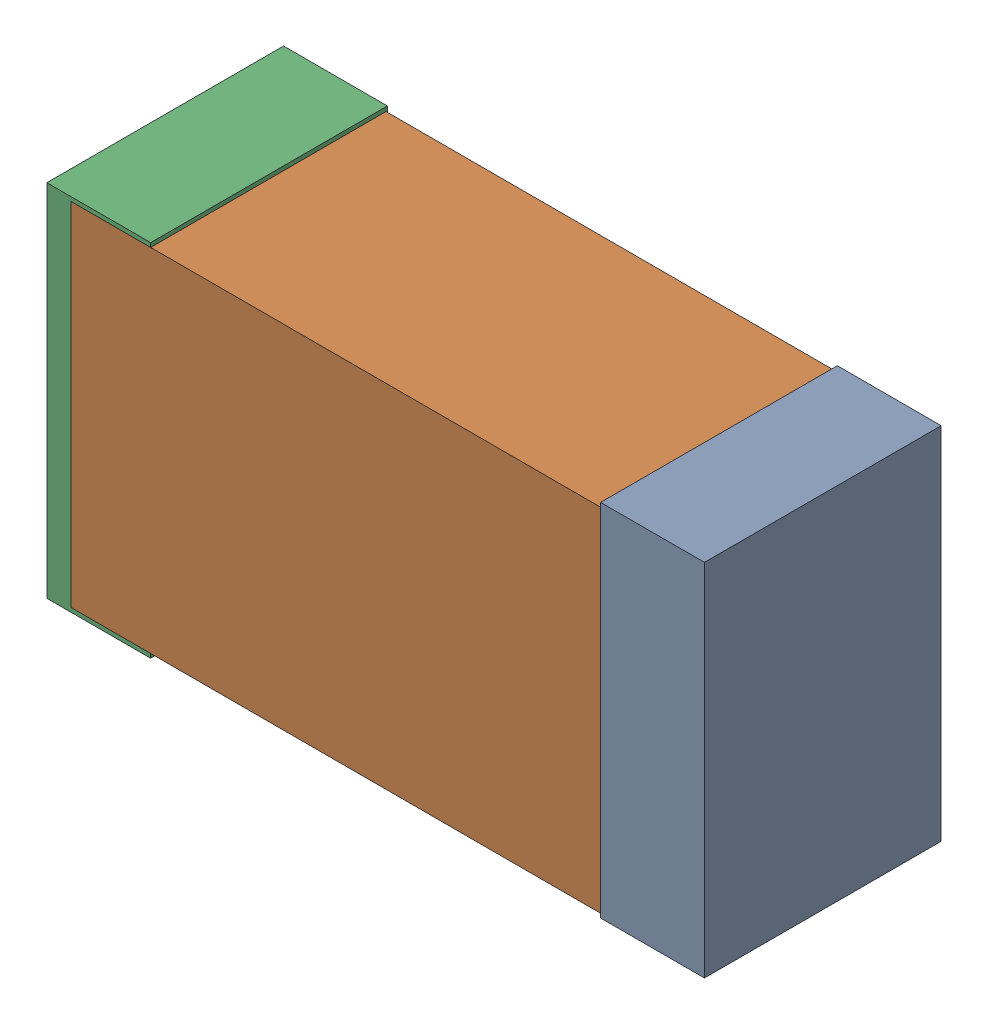
SolidWorks assembly USB45_C8, configuration Default. Lengths in mm.
Overall size (2.38 1.3 0.85).
6 component instances, 2 part files, 0 mates.
Components (placement in the parent):
- 384311232-1: 384311232 [Default] at (157.718 41.402 -1.9574) size (0.38 1.3 0.85)
  - Extruded_8-1: Extruded_8 [Default] at origin size (0.38 1.3 0.85)
- 384311360-1: 384311360 [Default] at (156.718 41.402 -1.9524) size (2.2 1.27 0.85)
  - Extruded_9-1: Extruded_9 [Default] at origin size (2.2 1.27 0.85)
- 384311232-2: 384311232 [Default] at (155.718 41.402 -1.9574) size (0.38 1.3 0.85)
  - Extruded_8-1: Extruded_8 [Default] at origin size (0.38 1.3 0.85)
